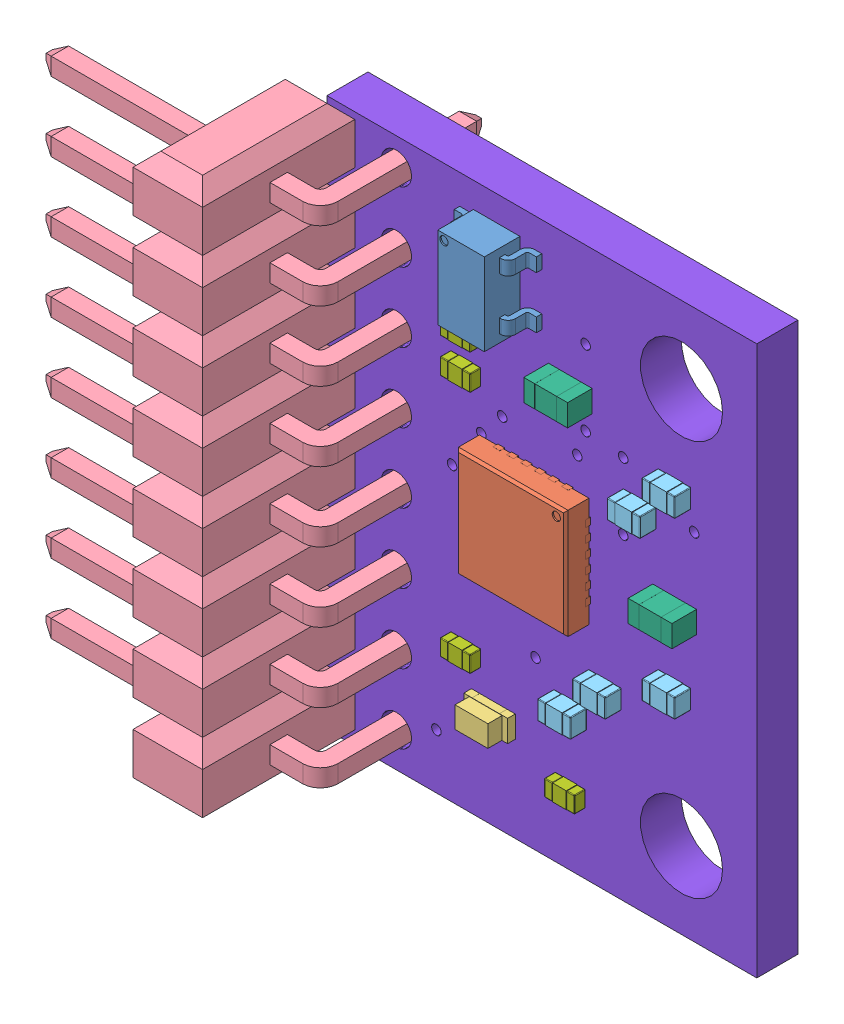
SolidWorks assembly mpu6050, configuration 默认. Lengths in mm.
Overall size (23.06 20.32 8.56).
18 component instances, 8 part files, 0 mates.
Components (placement in the parent):
- mpu6050schem.stp-1: mpu6050schem.stp [默认] at origin size (23.06 20.32 8.56)
  - Packages.stp-1: Packages.stp [默认] at origin size (20.86 20.32 8.56)
    - SOT95P295X145-5N.stp-1: SOT95P295X145-5N.stp [默认] at (6.35 17.78 1.5) size (3 3 1.45)
    - QFN50P395X395X90-25T265X255N.stp-1: QFN50P395X395X90-25T265X255N.stp [默认] at (7.62 10.16 1.5) x (0 -1 0) z (0 0 1) size (4 4 0.9)
    - CHIP-LED0603.stp-1: CHIP-LED0603.stp [默认] at (6.08 3.54 1.5) x (0 -1 0) z (0 0 1) size (0.8 1.6 0.8)
    - HDRRA8W64P254_1X8_2032X254X556B.stp-1: HDRRA8W64P254_1X8_2032X254X556B.stp [默认] at (2.54 10.16 1.5) x (0 -1 0) z (0 0 1) size (20.32 10.22 8.56)
    - C0402.stp-1: C0402.stp [默认] at (11.43 12.7 1.5) size (1.2 0.7 0.6)
    - C0402.stp-2: C0402.stp [默认] at (12.7 13.97 1.5) size (1.2 0.7 0.6)
    - C0402.stp-3: C0402.stp [默认] at (10.16 6.35 1.5) size (1.2 0.7 0.6)
    - C0402.stp-4: C0402.stp [默认] at (12.7 7.62 1.5) size (1.2 0.7 0.6)
    - C0402.stp-5: C0402.stp [默认] at (8.89 5.08 1.5) size (1.2 0.7 0.6)
    - C0603.stp-1: C0603.stp [默认] at (12.7 10.16 1.5) size (1.6 0.8 0.9)
    - C0603.stp-2: C0603.stp [默认] at (8.89 15.24 1.5) size (1.6 0.8 0.9)
    - R0402.stp-1: R0402.stp [默认] at (5.08 5.08 1.5) size (1.1 0.6 0.4)
    - R0402.stp-2: R0402.stp [默认] at (8.89 2.54 1.5) x (-1 0 0) z (0 0 1) size (1.1 0.6 0.4)
    - R0402.stp-3: R0402.stp [默认] at (5.08 13.97 1.5) size (1.1 0.6 0.4)
    - R0402.stp-4: R0402.stp [默认] at (5.08 15.24 1.5) size (1.1 0.6 0.4)
  - Board.stp-1: Board.stp [默认] at origin size (15.7 20.05 1.5)
